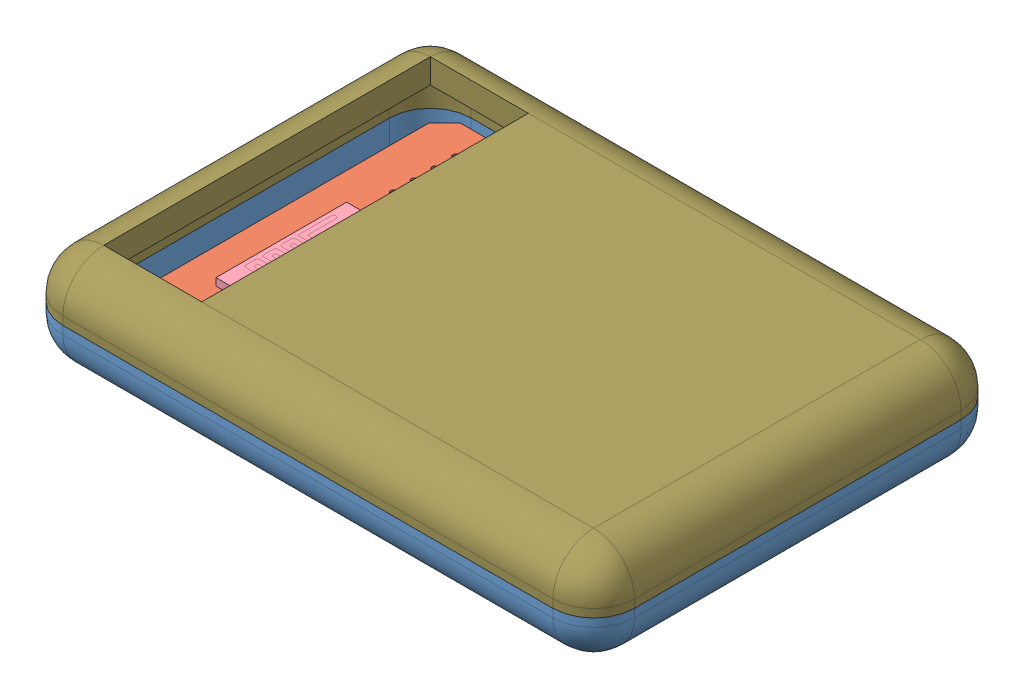
SolidWorks assembly Assem1, configuration Default. Lengths in mm.
Overall size (70 18 50).
308 component instances, 31 part files, 8 mates.
Components (placement in the parent):
- Part1-1: Part1 [Default] at (20.9181 15.1555 51.0174) size (70 6 50)
- he hee.step-1: he hee.step [Default] at (-8.5993 20.6955 72.1727) x (1 0 0) z (0 1 0) size (59.06 42.42 4.91)
  - Board.step-1: Board.step [Default] at origin size (59.06 42.42 0.51)
    - Open CASCADE STEP translator 7.5 1.1.1.step-1: Open CASCADE STEP translator 7.5 1.1.1.step [Default] at (0 0 -0.5069) size (59.06 42.42 0.51)
  - R5.step-1: R5.step [Default] at origin size (3.2 1.6 0.55)
    - 6081638016.step-1: 6081638016.step [Default] at (8.951 7.521 0.01) x (1 0 0) z (0 -1 0) size (3.2 0.55 1.6)
  - R4.step-1: R4.step [Default] at origin size (3.2 1.6 0.55)
    - 6081638016.step-1: 6081638016.step [Default] at (14.92 7.521 0.01) x (1 0 0) z (0 -1 0) size (3.2 0.55 1.6)
  - R3.step-1: R3.step [Default] at origin size (3.2 1.6 0.55)
    - 6081638016.step-1: 6081638016.step [Default] at (20.762 7.394 0.01) x (1 0 0) z (0 -1 0) size (3.2 0.55 1.6)
  - R2.step-1: R2.step [Default] at origin size (3.2 1.6 0.55)
    - 6081638016.step-1: 6081638016.step [Default] at (26.731 7.521 0.01) x (1 0 0) z (0 -1 0) size (3.2 0.55 1.6)
  - R1.step-1: R1.step [Default] at origin size (3.2 1.6 0.55)
    - 6081638016.step-1: 6081638016.step [Default] at (32.319 7.267 0.01) x (1 0 0) z (0 -1 0) size (3.2 0.55 1.6)
  - ESP8266.step-1: ESP8266.step [Default] at origin size (24 16 3)
    - 5667797072.step-1: 5667797072.step [Default] at (16.256 18.161 0) x (0 1 0) z (1 0 0) size (16 3 24)
  - C2.step-1: C2.step [Default] at origin size (1 0.55 0.5)
    - 6081638176.step-1: 6081638176.step [Default] at (37.955 5.969 0) size (1 0.55 0.5)
      - Fillet1.step-1: Fillet1.step [Default] at origin size (0.2 0.55 0.5)
      - Fillet2.step-1: Fillet2.step [Default] at origin size (0.2 0.55 0.5)
      - body2.step-1: body2.step [Default] at origin size (0.6 0.54 0.49)
  - C1.step-1: C1.step [Default] at origin size (1 0.55 0.5)
    - 6081638176.step-1: 6081638176.step [Default] at (37.955 7.239 0) size (1 0.55 0.5)
      - Fillet1.step-1: Fillet1.step [Default] at origin size (0.2 0.55 0.5)
      - Fillet2.step-1: Fillet2.step [Default] at origin size (0.2 0.55 0.5)
      - body2.step-1: body2.step [Default] at origin size (0.6 0.54 0.49)
  - R4-7.step-1: R4-7.step [Default] at origin size (1.6 3.2 0.55)
    - 6395201216.step-1: 6395201216.step [Default] at (15.268 18.857 -0.5169) x (0 1 0) z (-1 0 0) size (3.2 0.55 1.6)
  - R4-6.step-1: R4-6.step [Default] at origin size (3.2 1.6 0.55)
    - 6081637376.step-1: 6081637376.step [Default] at (53.66 17.173 -0.5169) x (-1 0 0) z (0 -1 0) size (3.2 0.55 1.6)
  - R4-5.step-1: R4-5.step [Default] at origin size (1.6 3.2 0.55)
    - 6395201216.step-1: 6395201216.step [Default] at (41.684 5.977 -0.5169) x (0 1 0) z (-1 0 0) size (3.2 0.55 1.6)
  - R4-4.step-1: R4-4.step [Default] at origin size (3.2 1.6 0.55)
    - 6081638016.step-1: 6081638016.step [Default] at (41.082 33.246 -0.5169) x (1 0 0) z (0 1 0) size (3.2 0.55 1.6)
  - R4-3.step-1: R4-3.step [Default] at origin size (3.2 1.6 0.55)
    - 6081638016.step-1: 6081638016.step [Default] at (35.494 33.246 -0.5169) x (1 0 0) z (0 1 0) size (3.2 0.55 1.6)
  - R4-2.step-1: R4-2.step [Default] at origin size (3.2 1.6 0.55)
    - 6081637376.step-1: 6081637376.step [Default] at (38.547 17.3 -0.5169) x (-1 0 0) z (0 -1 0) size (3.2 0.55 1.6)
  - R4-1.step-1: R4-1.step [Default] at origin size (3.2 1.6 0.55)
    - 6081637376.step-1: 6081637376.step [Default] at (27.953 17.046 -0.5169) x (-1 0 0) z (0 -1 0) size (3.2 0.55 1.6)
  - R3-7.step-1: R3-7.step [Default] at origin size (1.6 3.2 0.55)
    - 6395201216.step-1: 6395201216.step [Default] at (12.347 18.857 -0.5169) x (0 1 0) z (-1 0 0) size (3.2 0.55 1.6)
  - R3-6.step-1: R3-6.step [Default] at origin size (3.2 1.6 0.55)
    - 6081637376.step-1: 6081637376.step [Default] at (48.76 17.173 -0.5169) x (-1 0 0) z (0 -1 0) size (3.2 0.55 1.6)
  - R3-5.step-1: R3-5.step [Default] at origin size (1.6 3.2 0.55)
    - 6395201216.step-1: 6395201216.step [Default] at (41.684 10.983 -0.5169) x (0 1 0) z (-1 0 0) size (3.2 0.55 1.6)
  - R3-4.step-1: R3-4.step [Default] at origin size (3.2 1.6 0.55)
    - 6081637376.step-1: 6081637376.step [Default] at (49.215 34.953 -0.5169) x (-1 0 0) z (0 -1 0) size (3.2 0.55 1.6)
  - R3-3.step-1: R3-3.step [Default] at origin size (3.2 1.6 0.55)
    - 6081637376.step-1: 6081637376.step [Default] at (33.721 34.826 -0.5169) x (-1 0 0) z (0 -1 0) size (3.2 0.55 1.6)
  - R3-2.step-1: R3-2.step [Default] at origin size (3.2 1.6 0.55)
    - 6081638016.step-1: 6081638016.step [Default] at (40.447 15.72 -0.5169) x (1 0 0) z (0 1 0) size (3.2 0.55 1.6)
  - R3-1.step-1: R3-1.step [Default] at origin size (3.2 1.6 0.55)
    - 6081638016.step-1: 6081638016.step [Default] at (29.726 15.466 -0.5169) x (1 0 0) z (0 1 0) size (3.2 0.55 1.6)
  - R2-7.step-1: R2-7.step [Default] at origin size (1.6 3.2 0.55)
    - 6395201216.step-1: 6395201216.step [Default] at (12.347 13.396 -0.5169) x (0 1 0) z (-1 0 0) size (3.2 0.55 1.6)
  - R2-6.step-1: R2-6.step [Default] at origin size (3.2 1.6 0.55)
    - 6081637376.step-1: 6081637376.step [Default] at (53.66 19.84 -0.5169) x (-1 0 0) z (0 -1 0) size (3.2 0.55 1.6)
  - R2-5.step-1: R2-5.step [Default] at origin size (1.6 3.2 0.55)
    - 6395201216.step-1: 6395201216.step [Default] at (44.351 5.903 -0.5169) x (0 1 0) z (-1 0 0) size (3.2 0.55 1.6)
  - R2-4.step-1: R2-4.step [Default] at origin size (3.2 1.6 0.55)
    - 6081638016.step-1: 6081638016.step [Default] at (41.082 30.706 -0.5169) x (1 0 0) z (0 1 0) size (3.2 0.55 1.6)
  - R2-3.step-1: R2-3.step [Default] at origin size (3.2 1.6 0.55)
    - 6081638016.step-1: 6081638016.step [Default] at (35.547 30.579 -0.5169) x (1 0 0) z (0 1 0) size (3.2 0.55 1.6)
  - R2-2.step-1: R2-2.step [Default] at origin size (3.2 1.6 0.55)
    - 6081637376.step-1: 6081637376.step [Default] at (38.547 19.967 -0.5169) x (-1 0 0) z (0 -1 0) size (3.2 0.55 1.6)
  - R2-1.step-1: R2-1.step [Default] at origin size (3.2 1.6 0.55)
    - 6081637376.step-1: 6081637376.step [Default] at (28.006 19.713 -0.5169) x (-1 0 0) z (0 -1 0) size (3.2 0.55 1.6)
  - R1-7.step-1: R1-7.step [Default] at origin size (1.6 3.2 0.55)
    - 6395201216.step-1: 6395201216.step [Default] at (15.014 13.396 -0.5169) x (0 1 0) z (-1 0 0) size (3.2 0.55 1.6)
  - R1-6.step-1: R1-6.step [Default] at origin size (3.2 1.6 0.55)
    - 6081637376.step-1: 6081637376.step [Default] at (48.76 19.84 -0.5169) x (-1 0 0) z (0 -1 0) size (3.2 0.55 1.6)
  - R1-5.step-1: R1-5.step [Default] at origin size (1.6 3.2 0.55)
    - 6395201216.step-1: 6395201216.step [Default] at (44.351 10.909 -0.5169) x (0 1 0) z (-1 0 0) size (3.2 0.55 1.6)
  - R1-4.step-1: R1-4.step [Default] at origin size (3.2 1.6 0.55)
    - 6081638016.step-1: 6081638016.step [Default] at (46.035 30.706 -0.5169) x (1 0 0) z (0 1 0) size (3.2 0.55 1.6)
  - R1-3.step-1: R1-3.step [Default] at origin size (3.2 1.6 0.55)
    - 6081638016.step-1: 6081638016.step [Default] at (30.541 30.579 -0.5169) x (1 0 0) z (0 1 0) size (3.2 0.55 1.6)
  - R1-2.step-1: R1-2.step [Default] at origin size (3.2 1.6 0.55)
    - 6081637376.step-1: 6081637376.step [Default] at (43.627 19.967 -0.5169) x (-1 0 0) z (0 -1 0) size (3.2 0.55 1.6)
  - R1-1.step-1: R1-1.step [Default] at origin size (3.2 1.6 0.55)
    - 6081637376.step-1: 6081637376.step [Default] at (32.959 19.713 -0.5169) x (-1 0 0) z (0 -1 0) size (3.2 0.55 1.6)
  - Q7.step-1: Q7.step [Default] at origin size (2.9 2.6 1.4)
    - 5107308288.step-1: 5107308288.step [Default] at (21.148 14.929 -0.5069) x (0 -1 0) z (0 0 -1) size (2.6 2.9 1.4)
      - Body.step-1: Body.step [Default] at origin size (1.43 2.9 1.34)
      - PinsArrayL.step-1: PinsArrayL.step [Default] at origin size (0.59 2.33 0.73)
      - FilletPinR.step-1: FilletPinR.step [Default] at origin size (0.59 0.42 0.73)
  - Q6.step-1: Q6.step [Default] at origin size (2.6 2.9 1.4)
    - 6081635696.step-1: 6081635696.step [Default] at (50.038 25.019 -0.5069) x (1 0 0) z (0 0 -1) size (2.6 2.9 1.4)
      - Body-0.step-1: Body-0.step [Default] at origin size (1.43 2.9 1.34)
      - PinsArrayL-1.step-1: PinsArrayL-1.step [Default] at origin size (0.59 2.33 0.73)
      - FilletPinR-2.step-1: FilletPinR-2.step [Default] at origin size (0.59 0.42 0.73)
  - Q5.step-1: Q5.step [Default] at origin size (2.9 2.6 1.4)
    - 5107308288.step-1: 5107308288.step [Default] at (49.53 9.652 -0.5069) x (0 -1 0) z (0 0 -1) size (2.6 2.9 1.4)
      - Body.step-1: Body.step [Default] at origin size (1.43 2.9 1.34)
      - PinsArrayL.step-1: PinsArrayL.step [Default] at origin size (0.59 2.33 0.73)
      - FilletPinR.step-1: FilletPinR.step [Default] at origin size (0.59 0.42 0.73)
  - Q4.step-1: Q4.step [Default] at origin size (2.6 2.9 1.4)
    - 6081636176.step-1: 6081636176.step [Default] at (44.831 25.654 -0.5069) x (-1 0 0) z (0 0 -1) size (2.6 2.9 1.4)
      - Body-3.step-1: Body-3.step [Default] at origin size (1.43 2.9 1.34)
      - PinsArrayL-4.step-1: PinsArrayL-4.step [Default] at origin size (0.59 2.33 0.73)
      - FilletPinR-5.step-1: FilletPinR-5.step [Default] at origin size (0.59 0.42 0.73)
  - Q3.step-1: Q3.step [Default] at origin size (2.6 2.9 1.4)
    - 6081635696.step-1: 6081635696.step [Default] at (34.671 25.4 -0.5069) x (1 0 0) z (0 0 -1) size (2.6 2.9 1.4)
      - Body-0.step-1: Body-0.step [Default] at origin size (1.43 2.9 1.34)
      - PinsArrayL-1.step-1: PinsArrayL-1.step [Default] at origin size (0.59 2.33 0.73)
      - FilletPinR-2.step-1: FilletPinR-2.step [Default] at origin size (0.59 0.42 0.73)
  - Q2.step-1: Q2.step [Default] at origin size (2.6 2.9 1.4)
    - 6081636176.step-1: 6081636176.step [Default] at (40.259 25.273 -0.5069) x (-1 0 0) z (0 0 -1) size (2.6 2.9 1.4)
      - Body-3.step-1: Body-3.step [Default] at origin size (1.43 2.9 1.34)
      - PinsArrayL-4.step-1: PinsArrayL-4.step [Default] at origin size (0.59 2.33 0.73)
      - FilletPinR-5.step-1: FilletPinR-5.step [Default] at origin size (0.59 0.42 0.73)
  - Q1-1.step-1: Q1-1.step [Default] at origin size (2.6 2.9 1.4)
    - 6081636176.step-1: 6081636176.step [Default] at (29.464 25.146 -0.5069) x (-1 0 0) z (0 0 -1) size (2.6 2.9 1.4)
      - Body-3.step-1: Body-3.step [Default] at origin size (1.43 2.9 1.34)
      - PinsArrayL-4.step-1: PinsArrayL-4.step [Default] at origin size (0.59 2.33 0.73)
      - FilletPinR-5.step-1: FilletPinR-5.step [Default] at origin size (0.59 0.42 0.73)
  - HX711-7.step-1: HX711-7.step [Default] at origin size (9.9 6 1.6)
    - 6161757360.step-1: 6161757360.step [Default] at (13.335 31.369 0) x (0 1 0) z (1 0 0) size (6 1.6 9.9)
  - HX711-6.step-1: HX711-6.step [Default] at origin size (6 9.9 1.6)
    - 6081637936.step-1: 6081637936.step [Default] at (41.656 27.559 0) x (1 0 0) z (0 -1 0) size (6 1.6 9.9)
  - HX711-5.step-1: HX711-5.step [Default] at origin size (6 9.9 1.6)
    - 6081637936.step-1: 6081637936.step [Default] at (41.656 15.367 0) x (1 0 0) z (0 -1 0) size (6 1.6 9.9)
  - HX711-4.step-1: HX711-4.step [Default] at origin size (6 9.9 1.6)
    - 6081637936.step-1: 6081637936.step [Default] at (49.784 27.686 0) x (1 0 0) z (0 -1 0) size (6 1.6 9.9)
  - HX711-3.step-1: HX711-3.step [Default] at origin size (6 9.9 1.6)
    - 6081637936.step-1: 6081637936.step [Default] at (49.784 15.494 0) x (1 0 0) z (0 -1 0) size (6 1.6 9.9)
  - HX711-2.step-1: HX711-2.step [Default] at origin size (6 9.9 1.6)
    - 6081637936.step-1: 6081637936.step [Default] at (34.16 14.986 0) x (1 0 0) z (0 -1 0) size (6 1.6 9.9)
  - HX711-1.step-1: HX711-1.step [Default] at origin size (6 9.9 1.6)
    - 6081637936.step-1: 6081637936.step [Default] at (33.785 27.559 0) x (1 0 0) z (0 -1 0) size (6 1.6 9.9)
  - C5-7.step-1: C5-7.step [Default] at origin size (1 0.55 0.5)
    - 5107082448.step-1: 5107082448.step [Default] at (17.925 18.034 -0.5069) x (-1 0 0) z (0 0 -1) size (1 0.55 0.5)
      - Fillet1-6.step-1: Fillet1-6.step [Default] at origin size (0.2 0.55 0.5)
      - Fillet2-7.step-1: Fillet2-7.step [Default] at origin size (0.2 0.55 0.5)
      - body2-8.step-1: body2-8.step [Default] at origin size (0.6 0.54 0.49)
  - C5-6.step-1: C5-6.step [Default] at origin size (0.55 1 0.5)
    - 6081637296.step-1: 6081637296.step [Default] at (52.959 21.844 -0.5069) x (0 1 0) z (0 0 -1) size (1 0.55 0.5)
      - Fillet1-9.step-1: Fillet1-9.step [Default] at origin size (0.2 0.55 0.5)
      - Fillet2-10.step-1: Fillet2-10.step [Default] at origin size (0.2 0.55 0.5)
      - body2-11.step-1: body2-11.step [Default] at origin size (0.6 0.54 0.49)
  - C5-5.step-1: C5-5.step [Default] at origin size (1 0.55 0.5)
    - 6081638176.step-1: 6081638176.step [Default] at (46.355 6.731 -0.5069) x (1 0 0) z (0 0 -1) size (1 0.55 0.5)
      - Fillet1.step-1: Fillet1.step [Default] at origin size (0.2 0.55 0.5)
      - Fillet2.step-1: Fillet2.step [Default] at origin size (0.2 0.55 0.5)
      - body2.step-1: body2.step [Default] at origin size (0.6 0.54 0.49)
  - C5-4.step-1: C5-4.step [Default] at origin size (0.55 1 0.5)
    - 6081637616.step-1: 6081637616.step [Default] at (41.91 28.72 -0.5069) x (0 -1 0) z (0 0 -1) size (1 0.55 0.5)
      - Fillet1-12.step-1: Fillet1-12.step [Default] at origin size (0.2 0.55 0.5)
      - Fillet2-13.step-1: Fillet2-13.step [Default] at origin size (0.2 0.55 0.5)
      - body2-14.step-1: body2-14.step [Default] at origin size (0.6 0.54 0.49)
  - C5-3.step-1: C5-3.step [Default] at origin size (0.55 1 0.5)
    - 6081637616.step-1: 6081637616.step [Default] at (37.592 28.575 -0.5069) x (0 -1 0) z (0 0 -1) size (1 0.55 0.5)
      - Fillet1-12.step-1: Fillet1-12.step [Default] at origin size (0.2 0.55 0.5)
      - Fillet2-13.step-1: Fillet2-13.step [Default] at origin size (0.2 0.55 0.5)
      - body2-14.step-1: body2-14.step [Default] at origin size (0.6 0.54 0.49)
  - C5-2.step-1: C5-2.step [Default] at origin size (0.55 1 0.5)
    - 6081637296.step-1: 6081637296.step [Default] at (37.084 22.098 -0.5069) x (0 1 0) z (0 0 -1) size (1 0.55 0.5)
      - Fillet1-9.step-1: Fillet1-9.step [Default] at origin size (0.2 0.55 0.5)
      - Fillet2-10.step-1: Fillet2-10.step [Default] at origin size (0.2 0.55 0.5)
      - body2-11.step-1: body2-11.step [Default] at origin size (0.6 0.54 0.49)
  - C5-1.step-1: C5-1.step [Default] at origin size (0.55 1 0.5)
    - 6081637296.step-1: 6081637296.step [Default] at (26.67 21.971 -0.5069) x (0 1 0) z (0 0 -1) size (1 0.55 0.5)
      - Fillet1-9.step-1: Fillet1-9.step [Default] at origin size (0.2 0.55 0.5)
      - Fillet2-10.step-1: Fillet2-10.step [Default] at origin size (0.2 0.55 0.5)
      - body2-11.step-1: body2-11.step [Default] at origin size (0.6 0.54 0.49)
  - C4-7.step-1: C4-7.step [Default] at origin size (1 0.55 0.5)
    - 5107082448.step-1: 5107082448.step [Default] at (17.925 16.637 -0.5069) x (-1 0 0) z (0 0 -1) size (1 0.55 0.5)
      - Fillet1-6.step-1: Fillet1-6.step [Default] at origin size (0.2 0.55 0.5)
      - Fillet2-7.step-1: Fillet2-7.step [Default] at origin size (0.2 0.55 0.5)
      - body2-8.step-1: body2-8.step [Default] at origin size (0.6 0.54 0.49)
  - C4-6.step-1: C4-6.step [Default] at origin size (0.55 1 0.5)
    - 6081637296.step-1: 6081637296.step [Default] at (51.562 21.844 -0.5069) x (0 1 0) z (0 0 -1) size (1 0.55 0.5)
      - Fillet1-9.step-1: Fillet1-9.step [Default] at origin size (0.2 0.55 0.5)
      - Fillet2-10.step-1: Fillet2-10.step [Default] at origin size (0.2 0.55 0.5)
      - body2-11.step-1: body2-11.step [Default] at origin size (0.6 0.54 0.49)
  - C4-5.step-1: C4-5.step [Default] at origin size (1 0.55 0.5)
    - 6081638176.step-1: 6081638176.step [Default] at (46.373 8.255 -0.5069) x (1 0 0) z (0 0 -1) size (1 0.55 0.5)
      - Fillet1.step-1: Fillet1.step [Default] at origin size (0.2 0.55 0.5)
      - Fillet2.step-1: Fillet2.step [Default] at origin size (0.2 0.55 0.5)
      - body2.step-1: body2.step [Default] at origin size (0.6 0.54 0.49)
  - C4-4.step-1: C4-4.step [Default] at origin size (0.55 1 0.5)
    - 6081637616.step-1: 6081637616.step [Default] at (43.434 28.72 -0.5069) x (0 -1 0) z (0 0 -1) size (1 0.55 0.5)
      - Fillet1-12.step-1: Fillet1-12.step [Default] at origin size (0.2 0.55 0.5)
      - Fillet2-13.step-1: Fillet2-13.step [Default] at origin size (0.2 0.55 0.5)
      - body2-14.step-1: body2-14.step [Default] at origin size (0.6 0.54 0.49)
  - C4-3.step-1: C4-3.step [Default] at origin size (0.55 1 0.5)
    - 6081637616.step-1: 6081637616.step [Default] at (36.195 28.575 -0.5069) x (0 -1 0) z (0 0 -1) size (1 0.55 0.5)
      - Fillet1-12.step-1: Fillet1-12.step [Default] at origin size (0.2 0.55 0.5)
      - Fillet2-13.step-1: Fillet2-13.step [Default] at origin size (0.2 0.55 0.5)
      - body2-14.step-1: body2-14.step [Default] at origin size (0.6 0.54 0.49)
  - C4-2.step-1: C4-2.step [Default] at origin size (0.55 1 0.5)
    - 6081637296.step-1: 6081637296.step [Default] at (38.481 22.098 -0.5069) x (0 1 0) z (0 0 -1) size (1 0.55 0.5)
      - Fillet1-9.step-1: Fillet1-9.step [Default] at origin size (0.2 0.55 0.5)
      - Fillet2-10.step-1: Fillet2-10.step [Default] at origin size (0.2 0.55 0.5)
      - body2-11.step-1: body2-11.step [Default] at origin size (0.6 0.54 0.49)
  - C4-1.step-1: C4-1.step [Default] at origin size (0.55 1 0.5)
    - 6081637616.step-1: 6081637616.step [Default] at (28.067 21.971 -0.5069) x (0 -1 0) z (0 0 -1) size (1 0.55 0.5)
      - Fillet1-12.step-1: Fillet1-12.step [Default] at origin size (0.2 0.55 0.5)
      - Fillet2-13.step-1: Fillet2-13.step [Default] at origin size (0.2 0.55 0.5)
      - body2-14.step-1: body2-14.step [Default] at origin size (0.6 0.54 0.49)
  - C3-7.step-1: C3-7.step [Default] at origin size (1 0.55 0.5)
    - 5107082448.step-1: 5107082448.step [Default] at (17.925 15.24 -0.5069) x (-1 0 0) z (0 0 -1) size (1 0.55 0.5)
      - Fillet1-6.step-1: Fillet1-6.step [Default] at origin size (0.2 0.55 0.5)
      - Fillet2-7.step-1: Fillet2-7.step [Default] at origin size (0.2 0.55 0.5)
      - body2-8.step-1: body2-8.step [Default] at origin size (0.6 0.54 0.49)
  - C3-6.step-1: C3-6.step [Default] at origin size (0.55 1 0.5)
    - 6081637296.step-1: 6081637296.step [Default] at (50.165 21.844 -0.5069) x (0 1 0) z (0 0 -1) size (1 0.55 0.5)
      - Fillet1-9.step-1: Fillet1-9.step [Default] at origin size (0.2 0.55 0.5)
      - Fillet2-10.step-1: Fillet2-10.step [Default] at origin size (0.2 0.55 0.5)
      - body2-11.step-1: body2-11.step [Default] at origin size (0.6 0.54 0.49)
  - C3-5.step-1: C3-5.step [Default] at origin size (1 0.55 0.5)
    - 6081638176.step-1: 6081638176.step [Default] at (46.373 9.652 -0.5069) x (1 0 0) z (0 0 -1) size (1 0.55 0.5)
      - Fillet1.step-1: Fillet1.step [Default] at origin size (0.2 0.55 0.5)
      - Fillet2.step-1: Fillet2.step [Default] at origin size (0.2 0.55 0.5)
      - body2.step-1: body2.step [Default] at origin size (0.6 0.54 0.49)
  - C3-4.step-1: C3-4.step [Default] at origin size (0.55 1 0.5)
    - 6081637616.step-1: 6081637616.step [Default] at (44.831 28.72 -0.5069) x (0 -1 0) z (0 0 -1) size (1 0.55 0.5)
      - Fillet1-12.step-1: Fillet1-12.step [Default] at origin size (0.2 0.55 0.5)
      - Fillet2-13.step-1: Fillet2-13.step [Default] at origin size (0.2 0.55 0.5)
      - body2-14.step-1: body2-14.step [Default] at origin size (0.6 0.54 0.49)
  - C3-3.step-1: C3-3.step [Default] at origin size (0.55 1 0.5)
    - 6081637616.step-1: 6081637616.step [Default] at (34.798 28.575 -0.5069) x (0 -1 0) z (0 0 -1) size (1 0.55 0.5)
      - Fillet1-12.step-1: Fillet1-12.step [Default] at origin size (0.2 0.55 0.5)
      - Fillet2-13.step-1: Fillet2-13.step [Default] at origin size (0.2 0.55 0.5)
      - body2-14.step-1: body2-14.step [Default] at origin size (0.6 0.54 0.49)
  - C3-2.step-1: C3-2.step [Default] at origin size (0.55 1 0.5)
    - 6081637296.step-1: 6081637296.step [Default] at (39.878 22.098 -0.5069) x (0 1 0) z (0 0 -1) size (1 0.55 0.5)
      - Fillet1-9.step-1: Fillet1-9.step [Default] at origin size (0.2 0.55 0.5)
      - Fillet2-10.step-1: Fillet2-10.step [Default] at origin size (0.2 0.55 0.5)
      - body2-11.step-1: body2-11.step [Default] at origin size (0.6 0.54 0.49)
  - C3-1.step-1: C3-1.step [Default] at origin size (0.55 1 0.5)
    - 6081637296.step-1: 6081637296.step [Default] at (29.464 21.989 -0.5069) x (0 1 0) z (0 0 -1) size (1 0.55 0.5)
      - Fillet1-9.step-1: Fillet1-9.step [Default] at origin size (0.2 0.55 0.5)
      - Fillet2-10.step-1: Fillet2-10.step [Default] at origin size (0.2 0.55 0.5)
      - body2-11.step-1: body2-11.step [Default] at origin size (0.6 0.54 0.49)
  - C2-7.step-1: C2-7.step [Default] at origin size (1 0.55 0.5)
    - 5107082448.step-1: 5107082448.step [Default] at (17.907 12.446 -0.5069) x (-1 0 0) z (0 0 -1) size (1 0.55 0.5)
      - Fillet1-6.step-1: Fillet1-6.step [Default] at origin size (0.2 0.55 0.5)
      - Fillet2-7.step-1: Fillet2-7.step [Default] at origin size (0.2 0.55 0.5)
      - body2-8.step-1: body2-8.step [Default] at origin size (0.6 0.54 0.49)
  - C2-6.step-1: C2-6.step [Default] at origin size (0.55 1 0.5)
    - 6081637296.step-1: 6081637296.step [Default] at (47.371 21.844 -0.5069) x (0 1 0) z (0 0 -1) size (1 0.55 0.5)
      - Fillet1-9.step-1: Fillet1-9.step [Default] at origin size (0.2 0.55 0.5)
      - Fillet2-10.step-1: Fillet2-10.step [Default] at origin size (0.2 0.55 0.5)
      - body2-11.step-1: body2-11.step [Default] at origin size (0.6 0.54 0.49)
  - C2-5.step-1: C2-5.step [Default] at origin size (1 0.55 0.5)
    - 6081638176.step-1: 6081638176.step [Default] at (46.355 12.446 -0.5069) x (1 0 0) z (0 0 -1) size (1 0.55 0.5)
      - Fillet1.step-1: Fillet1.step [Default] at origin size (0.2 0.55 0.5)
      - Fillet2.step-1: Fillet2.step [Default] at origin size (0.2 0.55 0.5)
      - body2.step-1: body2.step [Default] at origin size (0.6 0.54 0.49)
  - C2-4.step-1: C2-4.step [Default] at origin size (0.55 1 0.5)
    - 6081637616.step-1: 6081637616.step [Default] at (47.625 28.72 -0.5069) x (0 -1 0) z (0 0 -1) size (1 0.55 0.5)
      - Fillet1-12.step-1: Fillet1-12.step [Default] at origin size (0.2 0.55 0.5)
      - Fillet2-13.step-1: Fillet2-13.step [Default] at origin size (0.2 0.55 0.5)
      - body2-14.step-1: body2-14.step [Default] at origin size (0.6 0.54 0.49)
  - C2-3.step-1: C2-3.step [Default] at origin size (0.55 1 0.5)
    - 6081637616.step-1: 6081637616.step [Default] at (31.75 28.575 -0.5069) x (0 -1 0) z (0 0 -1) size (1 0.55 0.5)
      - Fillet1-12.step-1: Fillet1-12.step [Default] at origin size (0.2 0.55 0.5)
      - Fillet2-13.step-1: Fillet2-13.step [Default] at origin size (0.2 0.55 0.5)
      - body2-14.step-1: body2-14.step [Default] at origin size (0.6 0.54 0.49)
  - C2-2.step-1: C2-2.step [Default] at origin size (0.55 1 0.5)
    - 6081637296.step-1: 6081637296.step [Default] at (42.672 22.116 -0.5069) x (0 1 0) z (0 0 -1) size (1 0.55 0.5)
      - Fillet1-9.step-1: Fillet1-9.step [Default] at origin size (0.2 0.55 0.5)
      - Fillet2-10.step-1: Fillet2-10.step [Default] at origin size (0.2 0.55 0.5)
      - body2-11.step-1: body2-11.step [Default] at origin size (0.6 0.54 0.49)
  - C2-1.step-1: C2-1.step [Default] at origin size (0.55 1 0.5)
    - 6081637296.step-1: 6081637296.step [Default] at (32.385 21.971 -0.5069) x (0 1 0) z (0 0 -1) size (1 0.55 0.5)
      - Fillet1-9.step-1: Fillet1-9.step [Default] at origin size (0.2 0.55 0.5)
      - Fillet2-10.step-1: Fillet2-10.step [Default] at origin size (0.2 0.55 0.5)
      - body2-11.step-1: body2-11.step [Default] at origin size (0.6 0.54 0.49)
  - C1-7.step-1: C1-7.step [Default] at origin size (1 0.55 0.5)
    - 5107082448.step-1: 5107082448.step [Default] at (17.889 13.843 -0.5069) x (-1 0 0) z (0 0 -1) size (1 0.55 0.5)
      - Fillet1-6.step-1: Fillet1-6.step [Default] at origin size (0.2 0.55 0.5)
      - Fillet2-7.step-1: Fillet2-7.step [Default] at origin size (0.2 0.55 0.5)
      - body2-8.step-1: body2-8.step [Default] at origin size (0.6 0.54 0.49)
  - C1-6.step-1: C1-6.step [Default] at origin size (0.55 1 0.5)
    - 6081637296.step-1: 6081637296.step [Default] at (48.768 21.844 -0.5069) x (0 1 0) z (0 0 -1) size (1 0.55 0.5)
      - Fillet1-9.step-1: Fillet1-9.step [Default] at origin size (0.2 0.55 0.5)
      - Fillet2-10.step-1: Fillet2-10.step [Default] at origin size (0.2 0.55 0.5)
      - body2-11.step-1: body2-11.step [Default] at origin size (0.6 0.54 0.49)
  - C1-5.step-1: C1-5.step [Default] at origin size (1 0.55 0.5)
    - 6081638176.step-1: 6081638176.step [Default] at (46.373 11.049 -0.5069) x (1 0 0) z (0 0 -1) size (1 0.55 0.5)
      - Fillet1.step-1: Fillet1.step [Default] at origin size (0.2 0.55 0.5)
      - Fillet2.step-1: Fillet2.step [Default] at origin size (0.2 0.55 0.5)
      - body2.step-1: body2.step [Default] at origin size (0.6 0.54 0.49)
  - C1-4.step-1: C1-4.step [Default] at origin size (0.55 1 0.5)
    - 6081637616.step-1: 6081637616.step [Default] at (46.228 28.72 -0.5069) x (0 -1 0) z (0 0 -1) size (1 0.55 0.5)
      - Fillet1-12.step-1: Fillet1-12.step [Default] at origin size (0.2 0.55 0.5)
      - Fillet2-13.step-1: Fillet2-13.step [Default] at origin size (0.2 0.55 0.5)
      - body2-14.step-1: body2-14.step [Default] at origin size (0.6 0.54 0.49)
  - C1-3.step-1: C1-3.step [Default] at origin size (0.55 1 0.5)
    - 6081637616.step-1: 6081637616.step [Default] at (33.274 28.575 -0.5069) x (0 -1 0) z (0 0 -1) size (1 0.55 0.5)
      - Fillet1-12.step-1: Fillet1-12.step [Default] at origin size (0.2 0.55 0.5)
      - Fillet2-13.step-1: Fillet2-13.step [Default] at origin size (0.2 0.55 0.5)
      - body2-14.step-1: body2-14.step [Default] at origin size (0.6 0.54 0.49)
  - C1-2.step-1: C1-2.step [Default] at origin size (0.55 1 0.5)
    - 6081637296.step-1: 6081637296.step [Default] at (41.275 22.098 -0.5069) x (0 1 0) z (0 0 -1) size (1 0.55 0.5)
      - Fillet1-9.step-1: Fillet1-9.step [Default] at origin size (0.2 0.55 0.5)
      - Fillet2-10.step-1: Fillet2-10.step [Default] at origin size (0.2 0.55 0.5)
      - body2-11.step-1: body2-11.step [Default] at origin size (0.6 0.54 0.49)
  - C1-1.step-1: C1-1.step [Default] at origin size (0.55 1 0.5)
    - 6081637296.step-1: 6081637296.step [Default] at (30.988 21.989 -0.5069) x (0 1 0) z (0 0 -1) size (1 0.55 0.5)
      - Fillet1-9.step-1: Fillet1-9.step [Default] at origin size (0.2 0.55 0.5)
      - Fillet2-10.step-1: Fillet2-10.step [Default] at origin size (0.2 0.55 0.5)
      - body2-11.step-1: body2-11.step [Default] at origin size (0.6 0.54 0.49)
- Part1 - Copy-1: Part1 - Copy [Default] at (20.9181 27.1555 51.0174) x (1 0 0) z (0 0 -1) size (70 6 50)
- Belt clip.step-1: Belt clip.step [Default] at (-8.2696 15.1555 58.8201) x (0 0 -1) z (-1 0 0) size (34.5 6 53)
Mates (geometry in assembly coordinates):
- Parallel1: parallel aligned: line of Part1-1 through (-11.0819 21.1555 34.0174) axis (0 0 1); line of he hee.step-1/Board.step-1/Open CASCADE STEP translator 7.5 1.1.1.step-1 through (-8.5993 20.6955 31.6597) axis (0 0 1)
- Parallel2: parallel aligned: line of Part1-1 through (47.9181 21.1555 29.0174) axis (-1 0 0); line of he hee.step-1/Board.step-1/Open CASCADE STEP translator 7.5 1.1.1.step-1 through (48.4237 20.6955 29.7547) axis (-1 0 0)
- Distance1: distance = 2.54 mm aligned: plane of he hee.step-1/Board.step-1/Open CASCADE STEP translator 7.5 1.1.1.step-1 through (20.8114 20.6955 50.929) normal (0 1 0); plane of Part1-1 through (20.9181 18.1555 51.0174) normal (0 1 0)
- Coincident4: coincident anti-aligned: plane of Part1-1 through (20.9181 21.1555 51.0174) normal (0 1 0); plane of Part1 - Copy-1 through (20.9181 21.1555 51.0174) normal (0 -1 0)
- Coincident5: coincident anti-aligned: line of Part1-1 through (55.9181 21.1555 71.0174) axis (0 0 -1); line of Part1 - Copy-1 through (55.9181 21.1555 31.0174) axis (0 0 1)
- Coincident6: coincident anti-aligned: line of Part1-1 through (50.9181 21.1555 26.0174) axis (-1 0 0); line of Part1 - Copy-1 through (-9.0819 21.1555 26.0174) axis (1 0 0)
- Coincident7: coincident anti-aligned: plane of Part1-1 through (20.9181 15.1555 51.0174) normal (0 -1 0); plane of Belt clip.step-1 through (6.7304 15.1555 43.8201) normal (0 1 0)
- Parallel3: parallel anti-aligned: line of Part1-1 through (-9.0819 15.1555 71.0174) axis (0 0 -1); line of Belt clip.step-1 through (-5.2696 9.1555 40.8201) axis (0 0 1)
